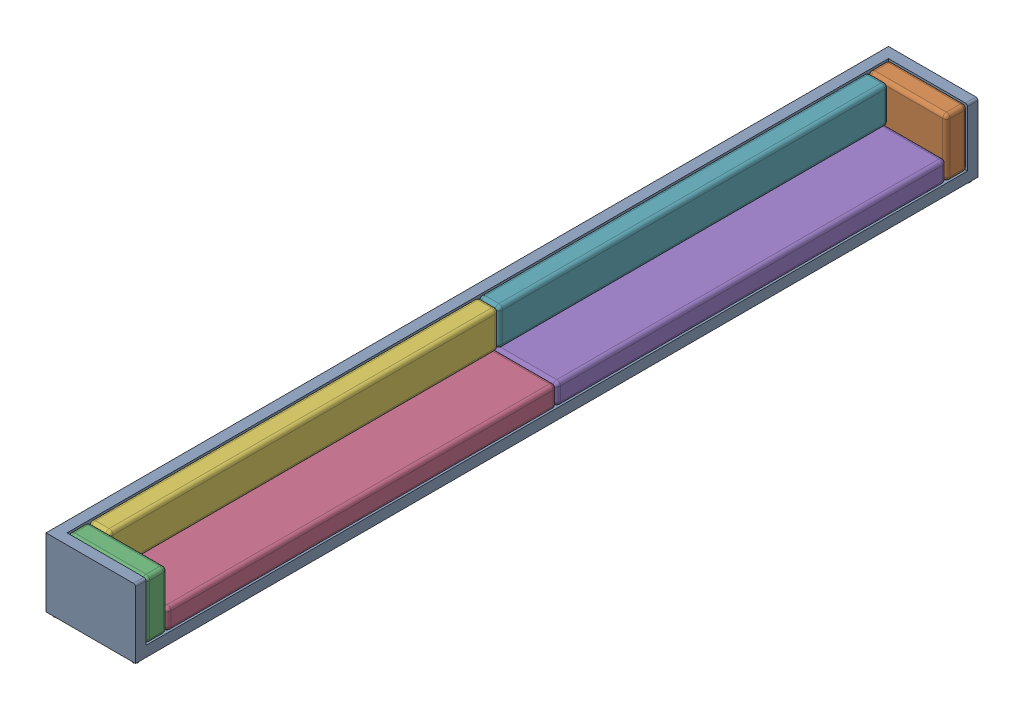
SolidWorks assembly assembled long sofa, configuration Default. Lengths in mm.
Overall size (850 680 8000).
7 component instances, 4 part files, 20 mates.
Components (placement in the parent):
- Long sofa body-1: Long sofa body [Default] at (-321.9425 108.8962 -3893.907) size (850 680 8000)
- Side cushion 1-1: Side cushion 1 [Default] at (-271.9425 261.6246 -3793.907) size (750 550 200)
- Side cushion 1-2: Side cushion 1 [Default] at (-271.9425 261.6246 3806.093) size (750 550 200)
- bottom cushion long sofa-1: bottom cushion long sofa [Default] at (-271.9425 -116.1038 1070.7876) size (750 200 3700)
- bottom cushion long sofa-2: bottom cushion long sofa [Default] at (-271.9425 -116.1038 -2629.2124) size (750 200 3700)
- Vertical cushion long sofa-1: Vertical cushion long sofa [Default] at (-446.9425 758.4432 1406.2534) x (0 0 1) z (-1 0 0) size (3700 350 200)
- Vertical cushion long sofa-2: Vertical cushion long sofa [Default] at (-446.9425 758.4432 -2293.7466) x (0 0 1) z (-1 0 0) size (3700 350 200)
Mates (geometry in assembly coordinates):
- Coincident1: coincident anti-aligned: plane of Long sofa body-1 through (103.0575 -116.1038 4006.093) normal (0 0 -1); plane of Side cushion 1-2 through (-271.9425 261.6246 4006.093) normal (0 0 1)
- Coincident2: coincident anti-aligned: plane of Long sofa body-1 through (-646.9425 -116.1038 -3793.907) normal (1 0 0); plane of Side cushion 1-2 through (-646.9425 433.8962 4006.093) normal (-1 0 0)
- Coincident3: coincident aligned: plane of Long sofa body-1 through (103.0575 -216.1038 4106.093) normal (1 0 0); plane of Side cushion 1-2 through (103.0575 433.8962 4006.093) normal (1 0 0)
- Coincident4: coincident anti-aligned: plane of Long sofa body-1 through (-646.9425 -116.1038 -3793.907) normal (0 0 1); plane of Side cushion 1-1 through (-271.9425 261.6246 -3793.907) normal (0 0 -1)
- Coincident5: coincident anti-aligned: plane of Long sofa body-1 through (-321.9425 -116.1038 -3893.907) normal (0 1 0); plane of Side cushion 1-1 through (-646.9425 -116.1038 -3593.907) normal (0 -1 0)
- Coincident6: coincident anti-aligned: plane of Long sofa body-1 through (-646.9425 -116.1038 -3793.907) normal (1 0 0); plane of Side cushion 1-1 through (-646.9425 433.8962 -3593.907) normal (-1 0 0)
- Parallel1: parallel anti-aligned: plane of Side cushion 1-1 through (-271.9425 261.6246 -3593.907) normal (0 0 1); plane of Side cushion 1-2 through (-271.9425 261.6246 3806.093) normal (0 0 -1)
- Coincident8: coincident anti-aligned: plane of Long sofa body-1 through (-321.9425 -116.1038 -3893.907) normal (0 1 0); plane of Side cushion 1-2 through (-646.9425 -116.1038 4006.093) normal (0 -1 0)
- Coincident9: coincident anti-aligned: plane of Long sofa body-1 through (-321.9425 -116.1038 -3893.907) normal (0 1 0); plane of bottom cushion long sofa-1 through (-271.9425 -116.1038 1070.7876) normal (0 -1 0)
- Coincident10: coincident anti-aligned: plane of Long sofa body-1 through (-321.9425 -116.1038 -3893.907) normal (0 1 0); plane of bottom cushion long sofa-2 through (-271.9425 -116.1038 -2629.2124) normal (0 -1 0)
- Coincident11: coincident anti-aligned: plane of bottom cushion long sofa-1 through (-646.9425 83.8962 106.093) normal (0 0 -1); plane of bottom cushion long sofa-2 through (-646.9425 83.8962 106.093) normal (0 0 1)
- Coincident12: coincident anti-aligned: plane of Long sofa body-1 through (-646.9425 -116.1038 -3793.907) normal (1 0 0); plane of bottom cushion long sofa-2 through (-646.9425 83.8962 -3593.907) normal (-1 0 0)
- Coincident13: coincident anti-aligned: plane of Side cushion 1-1 through (-271.9425 261.6246 -3593.907) normal (0 0 1); plane of bottom cushion long sofa-2 through (-646.9425 83.8962 -3593.907) normal (0 0 -1)
- Coincident14: coincident anti-aligned: plane of Long sofa body-1 through (-646.9425 -116.1038 -3793.907) normal (1 0 0); plane of bottom cushion long sofa-1 through (-646.9425 83.8962 106.093) normal (-1 0 0)
- Coincident15: coincident anti-aligned: plane of Vertical cushion long sofa-1 through (-646.9425 433.8962 -646.2818) normal (0 0 -1); plane of Vertical cushion long sofa-2 through (-646.9425 433.8962 -646.2818) normal (0 0 1)
- Coincident17: coincident anti-aligned: plane of Long sofa body-1 through (-646.9425 -116.1038 -3793.907) normal (1 0 0); plane of Vertical cushion long sofa-1 through (-646.9425 758.4432 1406.2534) normal (-1 0 0)
- Coincident18: coincident anti-aligned: plane of Long sofa body-1 through (-646.9425 -116.1038 -3793.907) normal (1 0 0); plane of Vertical cushion long sofa-2 through (-646.9425 758.4432 -2293.7466) normal (-1 0 0)
- Coincident19: coincident anti-aligned: plane of bottom cushion long sofa-1 through (-271.9425 83.8962 1070.7876) normal (0 1 0); plane of Vertical cushion long sofa-1 through (-646.9425 83.8962 106.093) normal (0 -1 0)
- Coincident20: coincident anti-aligned: plane of bottom cushion long sofa-2 through (-271.9425 83.8962 -2629.2124) normal (0 1 0); plane of Vertical cushion long sofa-2 through (-646.9425 83.8962 -3593.907) normal (0 -1 0)
- Coincident21: coincident anti-aligned: plane of Side cushion 1-2 through (-271.9425 261.6246 3806.093) normal (0 0 -1); plane of Vertical cushion long sofa-1 through (-646.9425 433.8962 3806.093) normal (0 0 1)
